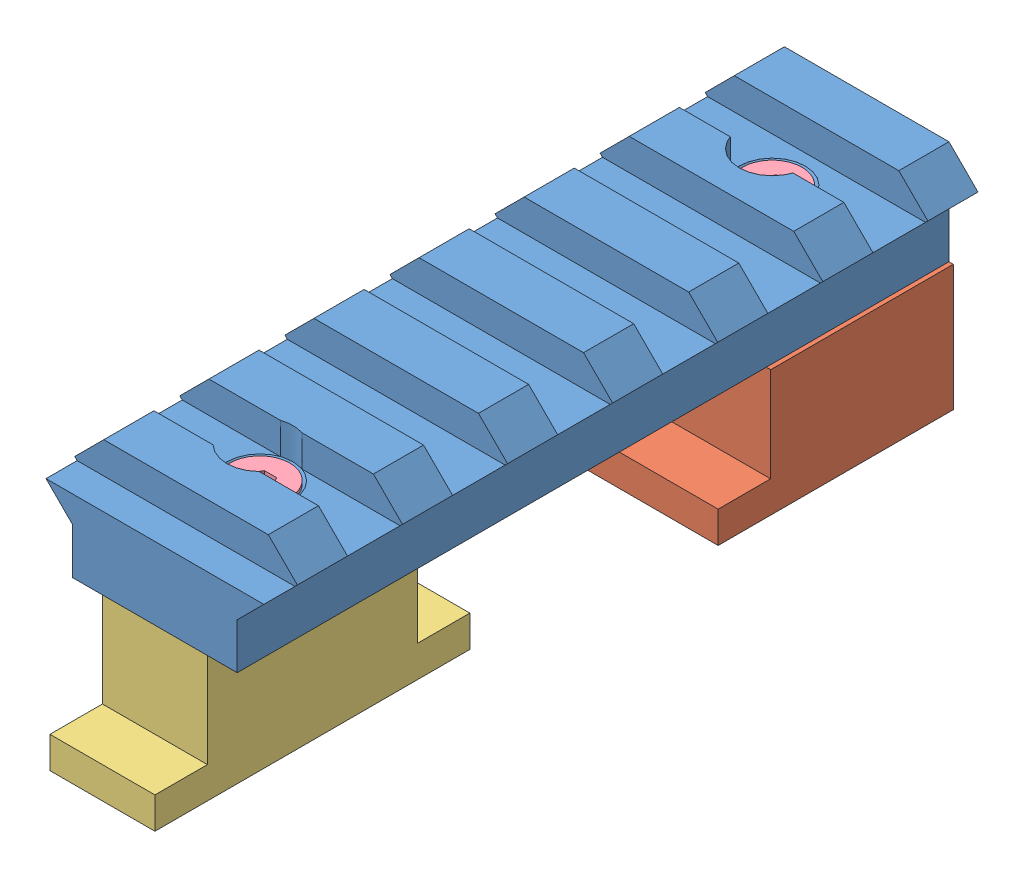
SolidWorks assembly Baugruppe1, configuration Standard. Lengths in mm.
Overall size (21.21 21.9 72.8).
5 component instances, 4 part files, 8 mates.
Components (placement in the parent):
- Rail-3: Rail [Standard] at (-4.1271 5.1584 0) size (21.21 9.9 67.8)
- flip_back-3: flip_back [Standard] at (-4.1271 -4.7457 0) x (0 0 1) z (-1 0 0) size (22.4 12 16.5)
- flip_front-1: flip_front [Standard] at (-4.1271 -4.7457 57.8) x (0 0 -1) z (1 0 0) size (30 12 10)
- Socket Countersunk Head Screw_DIN-4: Socket Countersunk Head Screw_DIN [DIN 7991 - M3 x 16 --- 12.8N] at (-4.1271 2.2084 9) x (0 -1 0) z (0 0 1) size (16 5.7 5.7)
- Socket Countersunk Head Screw_DIN-5: Socket Countersunk Head Screw_DIN [DIN 7991 - M3 x 16 --- 12.8N] at (-4.1271 2.2112 57.8) x (0 -1 0) z (0 0 1) size (16 5.7 5.7)
Mates (geometry in assembly coordinates):
- Deckungsgleich6: coincident: moEndPointRef_w of Rail-3; moEndPointRef_w of flip_back-3
- Deckungsgleich7: coincident anti-aligned: plane of Rail-3 through (-11.963 -4.7457 67.8) normal (0 -1 0); plane of flip_back-3 through (-12.3771 -4.7457 0) normal (0 1 0)
- Deckungsgleich8: coincident anti-aligned: line of Rail-3 through (-11.963 -4.7457 0) axis (1 0 0); line of flip_back-3 through (4.1229 -4.7457 0) axis (-1 0 0)
- Deckungsgleich9: coincident aligned: plane of Rail-3 through (-4.1271 12.9943 67.8) normal (0 0 1); plane of flip_front-1 through (0.8729 -13.7457 67.8) normal (0 0 1)
- Deckungsgleich10: coincident: moEndPointRef_w of flip_front-1; moEndPointRef_w of Rail-3
- Deckungsgleich11: coincident anti-aligned: plane of Rail-3 through (-11.963 -4.7457 67.8) normal (0 -1 0); plane of flip_front-1 through (0.8729 -4.7457 72.8) normal (0 1 0)
- Deckungsgleich15: coincident aligned: cone of Rail-3 through (-4.1271 2.1612 57.8) axis (0 -1 0); cone of Socket Countersunk Head Screw_DIN-5 through (-4.1271 1.8612 57.8) axis (0 -1 0)
- Deckungsgleich16: coincident aligned: cone of Rail-3 through (-4.1271 2.1584 9) axis (0 -1 0); cone of Socket Countersunk Head Screw_DIN-4 through (-4.1271 1.8584 9) axis (0 -1 0)
